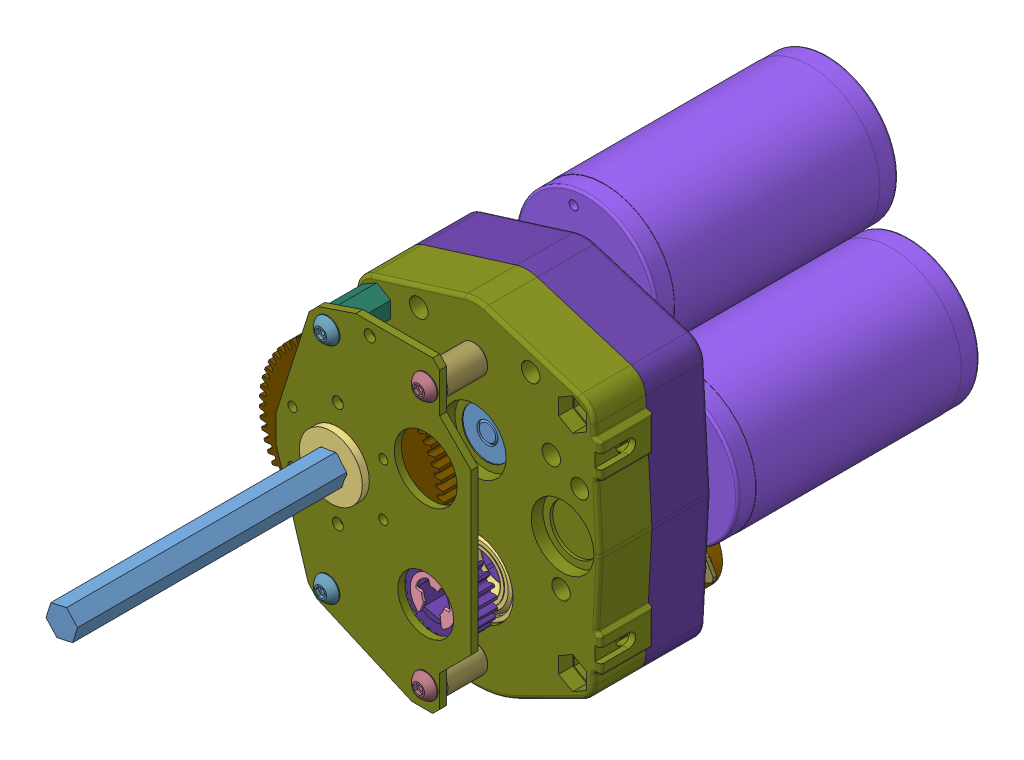
SolidWorks assembly 217-3268-STEP, configuration Default. Lengths in mm.
Overall size (164.35 174.72 312.65).
70 component instances, 40 part files, 0 mates.
Components (placement in the parent):
- 217-2733-1: 217-2733 [Default] at (0 53.4162 37.6682) x (0 0 1) z (-0.00054 -1 0) size (7.11 24.61 24.61)
- 217-2733-2: 217-2733 [Default] at (0 53.4162 7.9248) x (0 0 -1) z (-0.038475 0.99926 0) size (7.11 24.61 24.61)
- 217-2731-1: 217-2731 [Default] at (0 0 -0.0127) x (1 0 0) z (0 -1 0) size (31.12 7.94 31.12)
- 217-2789-1: 217-2789 [Default] at (0 0 43.2943) x (0 0 -1) z (0.998073 -0.062043 0) size (11.1 38.4 38.4)
- 217-2428-027 Rev1_97414A630-1: 217-2428-027 Rev1_97414A630 [Default] at (0 0 -6.5151) x (0 0 1) z (0.453751 0.891129 0) size (0.64 5.89 7.9)
- 217-2788_57155K375-1: 217-2788_57155K375 [Default] at (-0.0022 0.3376 -8.4201) x (0.971787 -0.235861 0) z (0 0 1) size (9.53 9.53 3.17)
- 217-2428-012 Rev3-1: 217-2428-012 Rev3 [Default] at (0 0 -40.386) size (63.5 22.23 2.29)
- 217-2428-027 Rev1_97414A630-2: 217-2428-027 Rev1_97414A630 [Default] at (0 0 -10.3251) x (0 0 1) z (-0.054891 -0.998492 0) size (0.64 5.89 7.9)
- 217-2428-005 Rev1-1: 217-2428-005 Rev1 [Default] at (25.4 0 -19.05) x (-0.557362 -0.83027 0) z (-0.83027 0.557362 0) size (7.33 38.98 6.35)
- 217-2428-005 Rev1-2: 217-2428-005 Rev1 [Default] at (-25.4 0 -19.05) x (0.667436 0.744667 0) z (0.744667 -0.667436 0) size (7.33 38.98 6.35)
- SCREW-832-0375-1: SCREW-832-0375 [Default] at (25.4 0 -42.5958) x (0 0 1) z (-0.875404 0.483392 0) size (11.73 7.92 7.92)
- SCREW-832-0375-2: SCREW-832-0375 [Default] at (-25.4 0 -42.5958) x (0 0 1) z (-0.966319 0.257347 0) size (11.73 7.92 7.92)
- SCREW-832-0375-3: SCREW-832-0375 [Default] at (25.4 0 5.3848) x (0 0 -1) z (1 0 0) size (11.73 7.92 7.92)
- SCREW-832-0375-4: SCREW-832-0375 [Default] at (-25.4 0 5.3848) x (0 0 -1) z (0.941463 -0.337115 0) size (11.73 7.92 7.92)
- SBS1_SBS-0632-0250-1: SBS1_SBS-0632-0250 [Default] at (15.494 0 -36.2458) x (0 0 -1) z (0.854303 -0.519775 0) size (8.57 6.68 6.65)
- SBS1_SBS-0632-0250-2: SBS1_SBS-0632-0250 [Default] at (-15.494 0 -36.2458) x (0 0 -1) z (0.854303 -0.519775 0) size (8.57 6.68 6.65)
- 217-2428-017 Rev2-1: 217-2428-017 Rev2 [Default] at (12.7 -21.997 -3.6517) x (-0.578458 -0.815712 0) z (0 0 -1) size (14.73 14.73 7.37)
- 217-2428-016 Rev2_Spur01-1: 217-2428-016 Rev2_Spur01 [Default] at (0 0 -3.6517) x (0.918689 -0.394983 0) z (0 0 1) size (40.67 40.74 13.3)
- 217-2428-019 Rev1-1: 217-2428-019 Rev1 [Default] at (12.7 -21.997 -20.6248) x (0.866025 0.5 0) z (0 0 1) size (50.8 19.05 1.57)
- 217-2428-006 Rev1-1: 217-2428-006 Rev1 [Default] at (32.079 -14.2875 -9.525) x (-0.95139 -0.30799 0) z (-0.30799 0.95139 0) size (7.33 19.93 6.35)
- 217-2428-006 Rev1-2: 217-2428-006 Rev1 [Default] at (-3.6662 -34.925 -9.525) x (-0.486716 0.87356 0) z (0.87356 0.486716 0) size (7.33 19.93 6.35)
- SCREW-832-0375-5: SCREW-832-0375 [Default] at (32.079 -14.2875 4.7498) x (0 0 -1) z (0.980613 0.195955 0) size (11.73 7.92 7.92)
- SCREW-832-0375-6: SCREW-832-0375 [Default] at (-3.6662 -34.925 5.3848) x (0 0 -1) z (-0.826375 -0.56312 0) size (11.73 7.92 7.92)
- SCREW-832-0375-7: SCREW-832-0375 [Default] at (-3.6662 -34.925 -22.8346) x (0 0 1) z (0.948865 0.315681 0) size (11.73 7.92 7.92)
- SCREW-832-0375-8: SCREW-832-0375 [Default] at (32.079 -14.2875 -22.8346) x (0 0 1) z (-0.875404 0.483392 0) size (11.73 7.92 7.92)
- 217-2614-001_12t-1: 217-2614-001_12t [Default] at (36.9798 39.6868 15.8623) x (0.996195 0.087156 0) z (0 0 1) size (18.29 18.29 19)
- 217-2761-001 rev1-1: 217-2761-001 rev1 [Default] at (36.6486 43.4723 16.1) x (-0.996195 -0.087156 0) z (0 0 1) size (2 2 20)
- 217-2761-001 rev1-2: 217-2761-001 rev1 [Default] at (-36.6486 43.4723 16.1) x (0.996195 -0.087156 0) z (0 0 1) size (2 2 20)
- 217-2614-001_12t-2: 217-2614-001_12t [Default] at (-36.9798 39.6868 15.8623) x (0.996195 -0.087156 0) z (0 0 1) size (18.29 18.29 19)
- 217-2614-001_12t-3: 217-2614-001_12t [Default] at (0 92.8624 15.8623) x (0.97459 0.223996 0) z (0 0 1) size (18.29 18.29 19)
- 217-2761-001 rev1-3: 217-2761-001 rev1 [Default] at (-0.8512 96.5658 16.1) x (0.97459 0.223996 0) z (0 0 1) size (2 2 20)
- 217-3195-002 rev1-1: 217-3195-002 rev1 [Default] at (0 0 50.546) x (-1 0 0) z (0 0 -1) size (114.31 152.24 24.96)
- 217-3195-001 Rev1-1: 217-3195-001 Rev1 [Default] at origin size (113.41 152.24 26.86)
- Nylock Nut_NNY2520-ZC-1: Nylock Nut_NNY2520-ZC [Default] at (48.8823 73.025 37.846) x (0 0.866025 -0.5) z (-1 0 0) size (12.85 11.89 7.62)
- Nylock Nut_NNY2520-ZC-2: Nylock Nut_NNY2520-ZC [Default] at (48.8823 -3.175 37.846) x (0 0 -1) z (-1 0 0) size (12.85 11.89 7.62)
- Nylock Nut_NNY2520-ZC-3: Nylock Nut_NNY2520-ZC [Default] at (44.45 85.725 7.8613) x (0 1 0) z (0 0 -1) size (12.85 11.89 7.62)
- Nylock Nut_NNY2520-ZC-4: Nylock Nut_NNY2520-ZC [Default] at (44.45 -15.875 7.8613) x (0 1 0) z (0 0 -1) size (12.85 11.89 7.62)
- 217-2428-004 Rev3-1: 217-2428-004 Rev3 [Default] at (0 53.4162 22.7711) x (0.360537 -0.932745 0) z (0 0 1) size (11 9.53 43.92)
- SBS1_SBS-2520-1625SS-1: SBS1_SBS-2520-1625SS [Default] at (44.45 85.725 42.4688) x (0 0 -1) z (-0.251219 0.96793 0) size (45.3 11.22 11.17)
- SBS1_SBS-2520-1625SS-2: SBS1_SBS-2520-1625SS [Default] at (44.45 -15.875 42.4688) x (0 0 -1) z (-0.251219 0.96793 0) size (45.3 11.22 11.17)
- SBS1_SBS2520-1750-1: SBS1_SBS2520-1750 [Default] at (-44.45 85.725 7.4422) x (0 0 1) z (-0.994188 -0.107657 0) size (48.48 11.22 11.17)
- SBS1_SBS2520-1750-2: SBS1_SBS2520-1750 [Default] at (-44.45 -15.875 7.4422) x (0 0 1) z (-0.994188 -0.107657 0) size (48.48 11.22 11.17)
- 217-2428-021 Rev1-1: 217-2428-021 Rev1 [Default] at (0 53.4162 9.5123) x (0.451333 -0.892356 0) z (0 0 1) size (15.88 15.88 3.17)
- 217-2428-029 Rev1-1: 217-2428-029 Rev1 [Default] at (0 53.4162 36.957) x (0.999846 0.017557 0) z (0 0 1) size (15.88 15.88 1.12)
- Grayhill Lock Washer-1: Grayhill Lock Washer [Default] at (12.7 -21.997 -18.6817) x (1 0 0) z (0 0 1) size (19.69 19.69 0.74)
- Grayhill Nut-1: Grayhill Nut [Default] at (12.7 -21.997 -17.0434) x (1 0 0) z (0 0 1) size (18.33 15.88 2.54)
- 217-2000-1: 217-2000 [Default] at (0 92.8624 0) x (0 0 -1) z (0.97459 0.223996 0) size (150.2 64.01 64.01)
- 217-2000-2: 217-2000 [Default] at (-36.9798 39.6868 0) x (0 0 -1) z (0.996195 -0.087156 0) size (150.2 64.01 64.01)
- 217-2000-3: 217-2000 [Default] at (36.9798 39.6868 0) x (0 0 -1) z (0.996195 0.087156 0) size (150.2 64.01 64.01)
- Grahill Encoder-1: Grahill Encoder [Default] at (12.7 -21.997 -16.1798) x (0.968646 -0.248444 0) z (0.248444 0.968646 0) size (31.75 31.12 31.75)
- 217-2711-001_50t-1: 217-2711-001_50t [Default] at (0 53.4162 17.4244) x (0.154138 0.988049 0) z (0 0 1) size (66.7 66.76 12.65)
- 217-3210-001 Rev1_30t-1: 217-3210-001 Rev1_30t [Default] at (0 53.4162 30.0736) x (0.778607 -0.627512 0) z (0 0 1) size (41.01 41.12 12.65)
- 217-3195-008 Rev1_stubby .75-1: 217-3195-008 Rev1_stubby .75 [Default] at (0 85.725 50.546) x (0.406184 -0.913791 0) z (0 0 1) size (12.7 12.7 19.05)
- 217-3195-008 Rev1_stubby .75-2: 217-3195-008 Rev1_stubby .75 [Default] at (0 -31.75 50.4952) x (0.334715 0.942319 0) z (0 0 1) size (12.7 12.7 19.05)
- Nylock Nut_NNY2520-ZC-5: Nylock Nut_NNY2520-ZC [Default] at (0 -31.75 45.0723) x (-0.5 0.866025 0) z (0 0 -1) size (12.85 11.89 7.62)
- Nylock Nut_NNY2520-ZC-6: Nylock Nut_NNY2520-ZC [Default] at (0 85.725 45.0723) x (-0.5 0.866025 0) z (0 0 -1) size (12.85 11.89 7.62)
- SBS1_SBS-2520-125-1: SBS1_SBS-2520-125 [Default] at (0 -31.75 76.1238) x (0 0 -1) z (0.656286 -0.754513 0) size (35.78 11.22 11.17)
- SBS1_SBS2520-0625ZC-1: SBS1_SBS2520-0625ZC [Default] at (-44.45 85.725 76.1238) x (0 0 -1) z (0.626272 -0.779605 0) size (19.57 11.22 11.17)
- SBS1_SBS2520-0625ZC-2: SBS1_SBS2520-0625ZC [Default] at (-44.45 -15.875 76.1238) x (0 0 -1) z (0.880271 -0.474471 0) size (19.57 11.22 11.17)
- SBS1_SBS-2520-125-2: SBS1_SBS-2520-125 [Default] at (0 85.725 76.1238) x (0 0 -1) z (0.323707 -0.946158 0) size (35.78 11.22 11.17)
- 217-2617-002 Rev1_91780A359-1: 217-2617-002 Rev1_91780A359 [Default] at (-44.45 -15.875 56.8452) x (-0.5 0.866025 0) z (0 0 -1) size (12.7 14.66 25.4)
- 217-2617-002 Rev1_91780A359-2: 217-2617-002 Rev1_91780A359 [Default] at (-44.45 85.725 56.8452) x (1 0 0) z (0 0 -1) size (12.7 14.66 25.4)
- 217-3195-003 rev2-1: 217-3195-003 rev2 [Default] at (0 0 72.771) size (88.62 139.7 3.17)
- 217-2704-001_24-1: 217-2704-001_24 [Default] at (-0.0127 0.0421 62.3062) x (-0.729505 0.683975 0) z (0 0 -1) size (33.29 33.29 12.65)
- 217-2715-001_64t-1: 217-2715-001_64t [Default] at (-39.878 35.5392 61.7541) x (0.954309 -0.29882 0) z (0 0 -1) size (84.3 84.3 12.65)
- 217-2617-003 Rev1-1: 217-2617-003 Rev1 [Default] at (-39.878 35.5392 121.8535) x (0.677046 -0.735941 0) z (0 0 1) size (14.66 12.7 152.4)
- 217-2743-1: 217-2743 [Default] at (-39.878 35.5392 49.1808) x (0 0 1) z (0.312889 -0.94979 0) size (7.94 28.58 28.58)
- 217-2734-1: 217-2734 [Default] at (-39.878 35.5392 75.946) x (0.399009 0.916947 0) z (-0.916947 0.399009 0) size (31.12 7.94 31.12)
- 217-2617-004 Rev1_97431A340_grv-1: 217-2617-004 Rev1_97431A340_grv [Default] at (0 0 69.0626) x (0 0 1) z (-0.124043 -0.992277 0) size (1.07 20.42 18.58)
- 217-2617-004 Rev1_97431A340_grv-2: 217-2617-004 Rev1_97431A340_grv [Default] at (-39.878 35.5392 54.8961) x (0 0 1) z (-0.124043 -0.992277 0) size (1.07 20.42 18.58)
